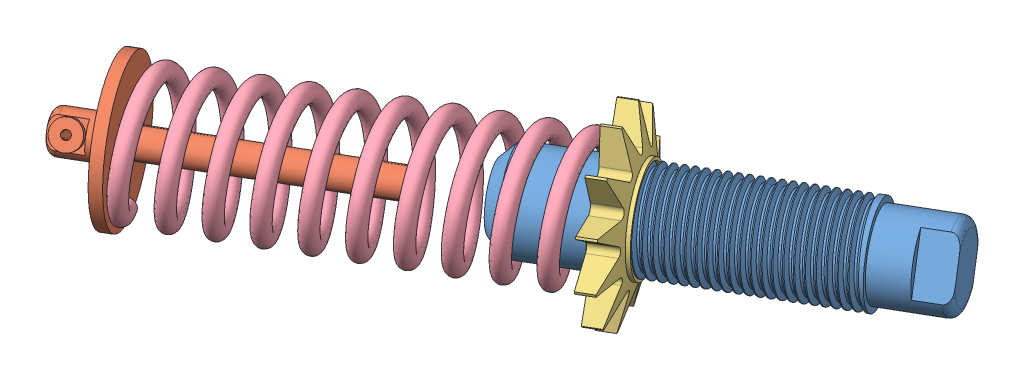
SolidWorks assembly suspension assembly, configuration Default. Lengths in mm.
Overall size (124.23 40.66 86.44).
4 component instances, 4 part files, 6 mates.
Components (placement in the parent):
- suspension top-1: suspension top [Default] at (36.4288 41.9104 60.8104) x (0.416423 0.507399 0.754412) z (-0.258562 0.86161 -0.436776) size (16 65.15 16)
- suspension base-1: suspension base [Default] at (-9.4989 41.216 86.6287) x (-0.419653 -0.496486 -0.759864) z (0.253287 -0.867945 0.427221) size (25 50.83 25)
- gear-1: gear [Default] at (49.7719 42.1122 53.3095) x (0.178523 0.922445 0.342381) z (-0.4565 0.385904 -0.801677) size (31.01 6.32 31.01)
- spring-1: spring [Default] at (49.7719 42.1122 53.3095) x (0.061263 -0.994729 0.082224) z (0.486322 0.101687 0.867842) size (23.72 72.04 26.56)
Mates (geometry in assembly coordinates):
- Concentric1: concentric aligned: cylinder of suspension top-1 through (75.6521 42.5035 38.7609) axis (-0.871629 -0.013179 0.489989) radius 2.5; cylinder of suspension base-1 through (27.1096 41.7695 66.0492) axis (-0.871629 -0.013179 0.489989) radius 2.5
- Concentric2: concentric aligned: cylinder of suspension top-1 through (82.6252 42.6089 34.841) axis (-0.871629 -0.013179 0.489989) radius 8; cylinder of gear-1 through (54.7402 42.1873 50.5166) axis (-0.871629 -0.013179 0.489989) radius 8.5
- Screw1: screw = 1 aligned: line of suspension top-1 through (82.6252 42.6089 34.841) axis (-0.871629 -0.013179 0.489989); cylinder of gear-1 through (54.7402 42.1873 50.5166) axis (-0.871629 -0.013179 0.489989) radius 8.5
- Concentric3: concentric aligned: cylinder of gear-1 through (54.7402 42.1873 50.5166) axis (-0.871629 -0.013179 0.489989) radius 8.5; line of spring-1 through (49.7719 42.1122 53.3095) axis (-0.871629 -0.013179 0.489989)
- Coincident6: coincident anti-aligned: plane of gear-1 through (49.7719 42.1122 53.3095) normal (-0.871629 -0.013179 0.489989); plane of spring-1 through (49.7719 42.1122 53.3095) normal (0.871629 0.013179 -0.489989)
- Coincident9: coincident anti-aligned: plane of suspension base-1 through (-7.7556 41.2424 85.6488) normal (0.871629 0.013179 -0.489989); plane of spring-1 through (-7.7556 41.2424 85.6488) normal (-0.871629 -0.013179 0.489989)
